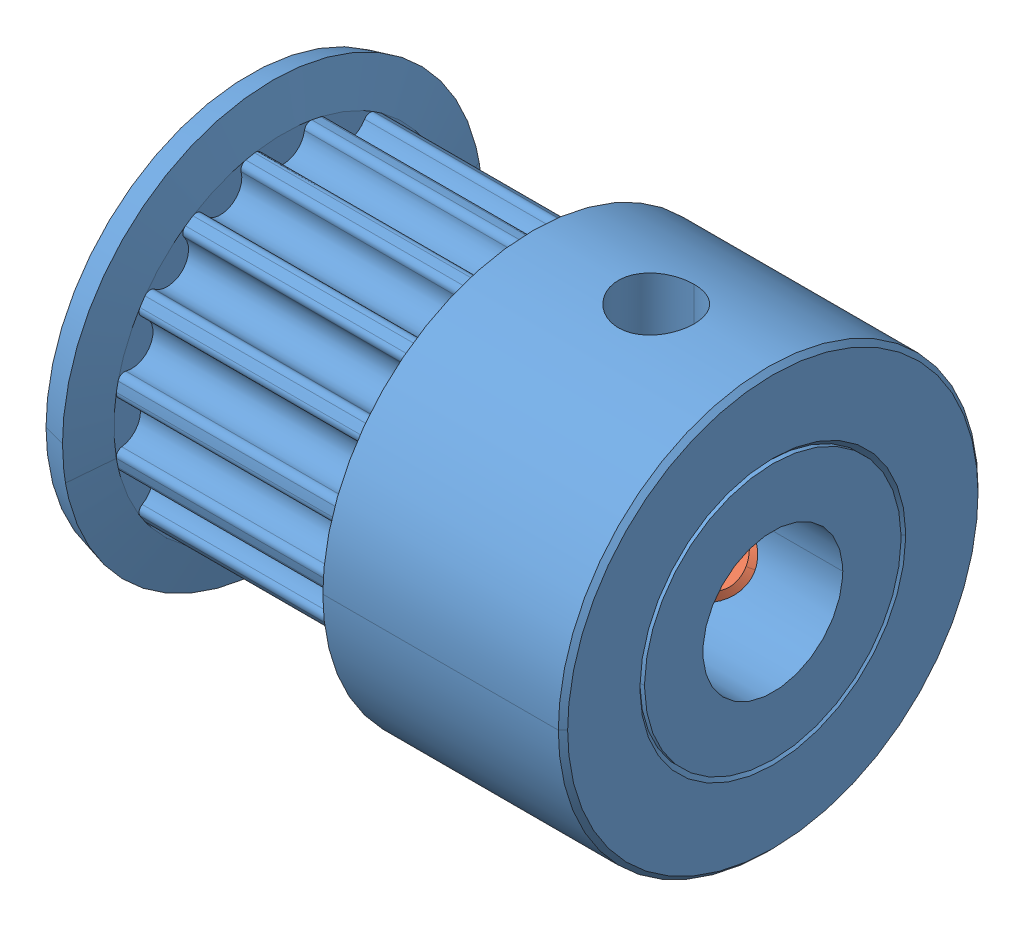
SolidWorks assembly GPA16MR3090_K_P6, configuration Default. Lengths in mm.
Overall size (23 18 18).
3 component instances, 2 part files, 0 mates.
Components (placement in the parent):
- _GPA16MR3090_K_P6_b_2-1: _GPA16MR3090_K_P6_b_2 [Default] at origin size (23 18 18)
- _SET_SCREW4_3_4-1: _SET_SCREW4_3_4 [Default] at (18 3 0) x (0 -1 0) z (-1 0 0) size (3 4 4)
- _SET_SCREW4_3_4-2: _SET_SCREW4_3_4 [Default] at (18 -1.5 -2.5981) x (0 0.5 0.866025) z (-1 0 0) size (3 4 4)
